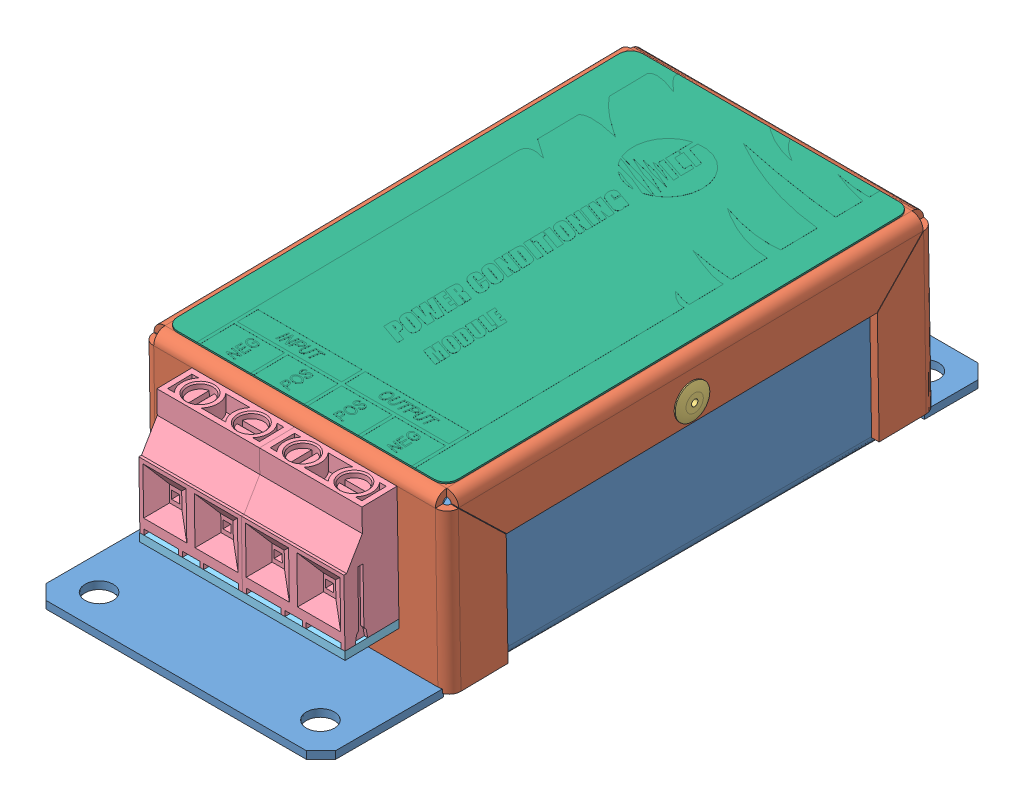
SolidWorks assembly PCM-25ADL - Noise Filter Assy, configuration Default. Lengths in mm.
Overall size (57.65 34.2 124.45).
8 component instances, 6 part files, 18 mates.
Components (placement in the parent):
- PCM-25ADL - Noise Filter Bottom Case-1: PCM-25ADL - Noise Filter Bottom Case [Default] at (48.3236 53.4655 92.7589) size (53.65 31 124.45)
- PCM-25ADL - Noise Filter Top Case-1: PCM-25ADL - Noise Filter Top Case [Default] at (48.3236 83.8648 87.8293) x (1 0 0) z (0 0.016279 -0.999867) size (56.45 31.8 90.5)
- Rivet-1: Rivet [Default] at (30.0986 78.0055 87.7339) x (0 -0.437784 -0.89908) z (0 0.89908 -0.437784) size (6.4 10.6 6.4)
- Rivet-2: Rivet [Default] at (66.5486 78.0055 87.7339) x (0 0 -1) z (0 -1 0) size (6.4 10.6 6.4)
- Dinkle EK950 Terminal Block - 2 Position-1: Dinkle EK950 Terminal Block - 2 Position [Default] at (29.3236 60.7317 142.71) x (1 0 0) z (0 -0.016279 0.999867) size (19.6 21.5 12.5)
- Dinkle EK950 Terminal Block - 2 Position-2: Dinkle EK950 Terminal Block - 2 Position [Default] at (48.3236 60.7317 142.71) x (1 0 0) z (0 -0.016279 0.999867) size (19.6 21.5 12.5)
- PCM-25ADL - Noise Filter - Circuit Board-1: PCM-25ADL - Noise Filter - Circuit Board [Default] at (48.2836 59.3337 136.4364) x (0 0.016279 -0.999867) z (1 0 0) size (12.5 1.5 38.08)
- PCM-25ADL - Noise Filter - Label-1: PCM-25ADL - Noise Filter - Label [Default] at (48.3236 85.2646 87.8521) x (0 0.016279 -0.999867) z (1 0 0) size (86.22 0.3 52)
Mates (geometry in assembly coordinates):
- Concentric1: concentric aligned: cylinder of PCM-25ADL - Noise Filter Bottom Case-1 through (21.4986 78.0055 87.7339) axis (1 0 0) radius 1.5; cylinder of PCM-25ADL - Noise Filter Top Case-1 through (20.0986 78.0055 87.7339) axis (1 0 0) radius 1.5
- Coincident1: coincident anti-aligned: plane of PCM-25ADL - Noise Filter Bottom Case-1 through (75.1486 53.4655 92.7589) normal (1 0 0); plane of PCM-25ADL - Noise Filter Top Case-1 through (75.1486 83.8648 87.8293) normal (-1 0 0)
- Concentric2: concentric aligned: cylinder of PCM-25ADL - Noise Filter Top Case-1 through (20.0986 78.0055 87.7339) axis (1 0 0) radius 1.5; cylinder of Rivet-1 through (30.0986 78.0055 87.7339) axis (1 0 0) radius 1.5
- Coincident2: coincident anti-aligned: plane of PCM-25ADL - Noise Filter Top Case-1 through (20.0986 83.8648 87.8293) normal (-1 0 0); plane of Rivet-1 through (20.0986 77.3489 86.3853) normal (1 0 0)
- Concentric3: concentric anti-aligned: cylinder of PCM-25ADL - Noise Filter Top Case-1 through (20.0986 78.0055 87.7339) axis (1 0 0) radius 1.5; cylinder of Rivet-2 through (66.5486 78.0055 87.7339) axis (-1 0 0) radius 1.5
- Coincident3: coincident anti-aligned: plane of PCM-25ADL - Noise Filter Top Case-1 through (76.5486 83.8648 87.8293) normal (1 0 0); plane of Rivet-2 through (76.5486 78.0055 86.2339) normal (-1 0 0)
- Coincident4: coincident anti-aligned: plane of Dinkle EK950 Terminal Block - 2 Position-1 through (48.3236 60.7317 142.71) normal (1 0 0); plane of Dinkle EK950 Terminal Block - 2 Position-2 through (48.3236 60.7317 142.71) normal (-1 0 0)
- Coincident5: coincident aligned: plane of Dinkle EK950 Terminal Block - 2 Position-1 through (48.3236 77.9864 139.4904) normal (0 -0.016279 0.999867); plane of Dinkle EK950 Terminal Block - 2 Position-2 through (67.3236 77.9864 139.4904) normal (0 -0.016279 0.999867)
- Coincident6: coincident aligned: plane of Dinkle EK950 Terminal Block - 2 Position-1 through (48.3236 82.2858 139.5604) normal (0 0.999867 0.016279); plane of Dinkle EK950 Terminal Block - 2 Position-2 through (67.3236 82.2858 139.5604) normal (0 0.999867 0.016279)
- Coincident7: coincident anti-aligned: plane of PCM-25ADL - Noise Filter Top Case-1 through (48.3236 83.1282 133.0733) normal (0 -0.016279 0.999867); plane of Dinkle EK950 Terminal Block - 2 Position-1 through (48.3236 82.3917 133.0613) normal (0 0.016279 -0.999867)
- Coincident8: coincident anti-aligned: line of PCM-25ADL - Noise Filter Top Case-1 through (22.2352 82.3917 133.0613) axis (1 0 0); line of Dinkle EK950 Terminal Block - 2 Position-1 through (48.3236 82.3917 133.0613) axis (-1 0 0)
- Width1: width aligned: plane of PCM-25ADL - Noise Filter Top Case-1 through (20.0986 83.8648 87.8293) normal (-1 0 0); plane of Dinkle EK950 Terminal Block - 2 Position-1 through (76.5486 83.8648 87.8293) normal (1 0 0); plane of PCM-25ADL - Noise Filter Top Case-1 through (29.3236 60.7317 142.71) normal (-1 0 0); plane of Dinkle EK950 Terminal Block - 2 Position-2 through (67.3236 60.7317 142.71) normal (1 0 0)
- Coincident9: coincident anti-aligned: plane of Dinkle EK950 Terminal Block - 2 Position-2 through (67.3236 60.9352 130.2116) normal (0 -0.999867 -0.016279); plane of PCM-25ADL - Noise Filter - Circuit Board-1 through (48.2836 60.8335 136.4608) normal (0 0.999867 0.016279)
- Coincident10: coincident aligned: plane of Dinkle EK950 Terminal Block - 2 Position-2 through (67.3236 60.7317 142.71) normal (1 0 0); plane of PCM-25ADL - Noise Filter - Circuit Board-1 through (67.3236 60.7317 142.71) normal (1 0 0)
- Coincident11: coincident aligned: plane of Dinkle EK950 Terminal Block - 2 Position-2 through (67.3236 60.7317 142.71) normal (0 -0.016279 0.999867); plane of PCM-25ADL - Noise Filter - Circuit Board-1 through (29.2436 60.7317 142.71) normal (0 -0.016279 0.999867)
- Coincident12: coincident anti-aligned: plane of PCM-25ADL - Noise Filter Top Case-1 through (48.3236 85.2646 87.8521) normal (0 0.999867 0.016279); plane of PCM-25ADL - Noise Filter - Label-1 through (24.5236 84.5986 128.7567) normal (0 -0.999867 -0.016279)
- Width2: width aligned: plane of PCM-25ADL - Noise Filter Top Case-1 through (76.5486 83.8648 87.8293) normal (1 0 0); plane of PCM-25ADL - Noise Filter - Label-1 through (20.0986 83.8648 87.8293) normal (-1 0 0); plane of PCM-25ADL - Noise Filter Top Case-1 through (74.3236 84.8786 128.7612) normal (1 0 0); plane of PCM-25ADL - Noise Filter - Label-1 through (22.3236 84.8786 128.7612) normal (-1 0 0)
- Width3: width aligned: plane of PCM-25ADL - Noise Filter Top Case-1 through (48.3236 83.1282 133.0733) normal (0 -0.016279 0.999867); plane of PCM-25ADL - Noise Filter - Label-1 through (48.3236 84.6014 42.5853) normal (0 0.016279 -0.999867); plane of PCM-25ADL - Noise Filter Top Case-1 through (24.5236 84.8428 130.9609) normal (0 -0.016279 0.999867); plane of PCM-25ADL - Noise Filter - Label-1 through (24.5236 86.2463 44.7524) normal (0 0.016279 -0.999867)
